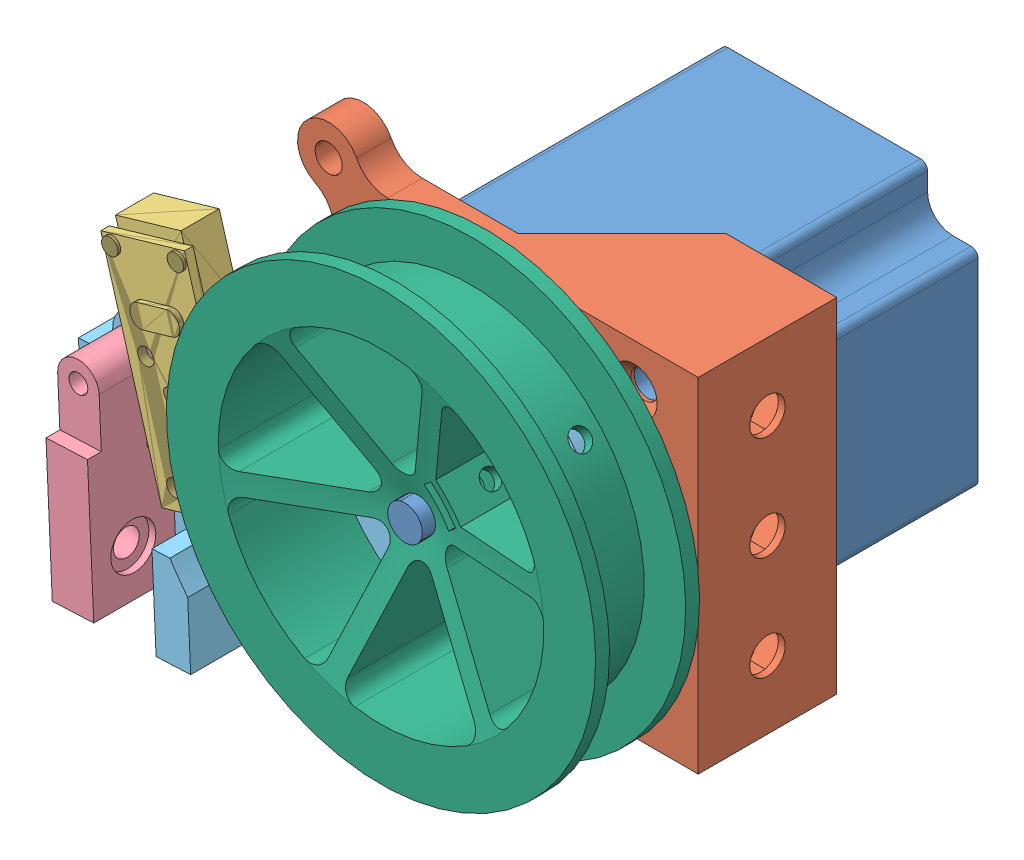
SolidWorks assembly rover_assembly2, configuration Default. Lengths in mm.
Overall size (127.22 111.12 81.28).
7 component instances, 6 part files, 10 mates.
Components (placement in the parent):
- anaheim_stepper_nema23-1: anaheim_stepper_nema23 [Default] at (3.6025 9.7468 4.1172) size (56.4 56.4 76.88)
- motor_plate-1: motor_plate [Default] at (3.6025 9.7468 11.4572) x (0 -1 0) z (0 0 -1) size (76.36 73.49 25.4)
- limit_assembly-1: limit_assembly [Default] at (-24.4841 -75.3325 45.228) x (-0.045306 0.998973 0) z (0 0 1) size (82.8 107.95 19.05)
  - mechanical_endstop-1: mechanical_endstop [Default] at (58.8161 21.2263 -22.6708) x (0.971653 0.236413 0) z (0 0 -1) size (41.88 19.5 9.76)
  - lever_bar-1: lever_bar [Default] at (59.5905 30.3176 -27.4208) size (38.1 7.62 15.24)
  - limit_plate3-1: limit_plate3 [Default] at (83.7195 -31.9124 -33.7708) size (82.8 107.95 19.05)
- string_pulley-1: string_pulley [Default] at (3.6025 9.7468 24.7922) x (-0.751113 -0.660173 0) z (0 0 -1) size (78.74 78.74 19.05)
Mates (geometry in assembly coordinates):
- Concentric1: concentric anti-aligned: cylinder of anaheim_stepper_nema23-1 through (3.6025 9.7468 10.5172) axis (0 0 -1) radius 19.05; cylinder of ? through (3.6025 9.7468 11.4572) axis (0 0 1) radius 25.4
- Concentric2: concentric aligned: cylinder of anaheim_stepper_nema23-1 through (3.6025 9.7468 29.9172) axis (0 0 -1) radius 3.175; cylinder of string_pulley-1 through (3.6025 9.7468 34.3172) axis (0 0 -1) radius 3.1115
- Distance1: distance = 1.27 mm anti-aligned: plane of ? through (3.5556 9.8648 13.9972) normal (0 0 1); plane of string_pulley-1 through (-25.7742 -16.464 15.2672) normal (0 0 -1)
- Concentric4: concentric aligned: circle of anaheim_stepper_nema23-1; cylinder of motor_plate-1 through (3.6025 9.7468 8.9172) axis (0 0 1) radius 19.812
- Parallel5: parallel anti-aligned: plane of anaheim_stepper_nema23-1 through (31.8025 -14.0082 8.9172) normal (1 0 0); plane of motor_plate-1 through (32.5645 33.5018 5.1072) normal (-1 0 0)
- Coincident11: coincident anti-aligned: plane of anaheim_stepper_nema23-1 through (-20.1525 33.5018 8.9172) normal (0 0 1); plane of motor_plate-1 through (-20.1525 -14.0082 8.9172) normal (0 0 -1)
- Coincident13: coincident anti-aligned: plane of motor_plate-1 through (-20.1525 -14.0082 11.4572) normal (0 0 1); plane of ? through (3.6025 9.7468 11.4572) normal (0 0 -1)
- Concentric5: concentric aligned: cylinder of anaheim_stepper_nema23-1 through (3.6025 9.7468 29.9172) axis (0 0 -1) radius 3.175; cylinder of limit_assembly-1/limit_plate3-1 through (3.6025 9.7468 13.9972) axis (0 0 -1) radius 3.81
- Coincident15: coincident anti-aligned: plane of motor_plate-1 through (-20.1525 -14.0082 11.4572) normal (0 0 1); plane of limit_assembly-1/limit_plate3-1 through (3.6025 9.7468 11.4572) normal (0 0 -1)
- Distance2: distance = 1.27 mm anti-aligned: plane of string_pulley-1 through (-25.9688 -16.2442 15.2672) normal (0 0 -1); plane of limit_assembly-1/limit_plate3-1 through (3.6025 9.7468 13.9972) normal (0 0 1)
